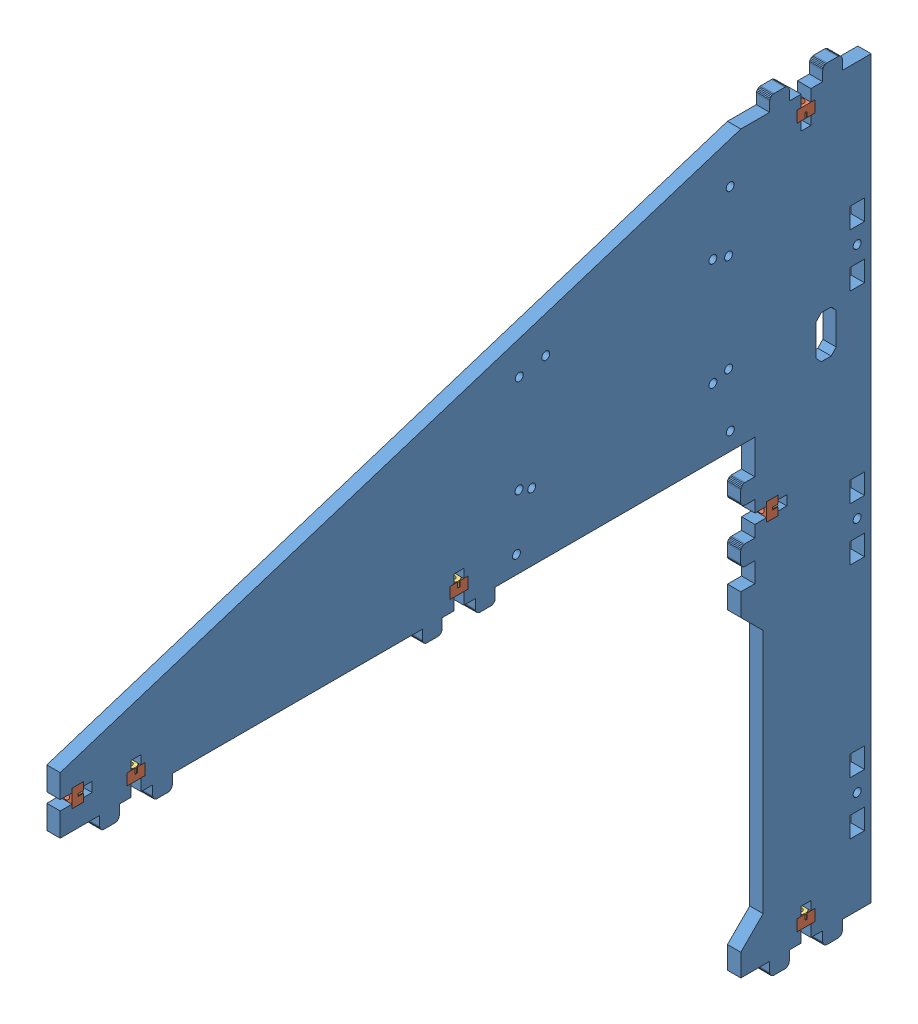
SolidWorks assembly Assembly Right Brace, configuration Valor predeterminado. Lengths in mm.
Overall size (7.94 342.6 363.9).
19 component instances, 3 part files, 21 mates.
Components (placement in the parent):
- Brace-1: Brace [Valor predeterminado] at (6 192.984 -281.4657) x (0 -1 0) z (-1 0 0) size (342.6 363.9 6)
- Assembly m3-nut-adapter + Nut DIN 934 - M3-1: Assembly m3-nut-adapter + Nut DIN 934 - M3 [Valor predeterminado] at (3 117.6 -228.1836) x (0 0 1) z (0 -1 0) size (8.25 7.94 5.1)
  - m3-nut-adapter-1: m3-nut-adapter [Valor predeterminado] at origin size (8 6 5.1)
  - Nut DIN 934 - M3-1: Nut DIN 934 - M3 [Valor predeterminado] at (0 0 3.9) x (0 0 1) z (-0.866025 -0.5 0) size (2.4 5.5 6.35)
- Assembly m3-nut-adapter + Nut DIN 934 - M3-2: Assembly m3-nut-adapter + Nut DIN 934 - M3 [Valor predeterminado] at (3 5.3 -72.4337) x (0 0 1) z (0 1 0) size (8.25 7.94 5.1)
  - m3-nut-adapter-1: m3-nut-adapter [Valor predeterminado] at origin size (8 6 5.1)
  - Nut DIN 934 - M3-1: Nut DIN 934 - M3 [Valor predeterminado] at (0 0 3.9) x (0 0 1) z (-0.866025 -0.5 0) size (2.4 5.5 6.35)
- Assembly m3-nut-adapter + Nut DIN 934 - M3-3: Assembly m3-nut-adapter + Nut DIN 934 - M3 [Valor predeterminado] at (3 5.3 72.4337) x (0 0 -1) z (0 1 0) size (8.25 7.94 5.1)
  - m3-nut-adapter-1: m3-nut-adapter [Valor predeterminado] at origin size (8 6 5.1)
  - Nut DIN 934 - M3-1: Nut DIN 934 - M3 [Valor predeterminado] at (0 0 3.9) x (0 0 1) z (-0.866025 -0.5 0) size (2.4 5.5 6.35)
- Assembly m3-nut-adapter + Nut DIN 934 - M3-4: Assembly m3-nut-adapter + Nut DIN 934 - M3 [Valor predeterminado] at (3 -31.7 -210.5336) x (0 -1 0) z (0 0 -1) size (8.25 7.94 5.1)
  - m3-nut-adapter-1: m3-nut-adapter [Valor predeterminado] at origin size (8 6 5.1)
  - Nut DIN 934 - M3-1: Nut DIN 934 - M3 [Valor predeterminado] at (0 0 3.9) x (0 0 1) z (-0.866025 -0.5 0) size (2.4 5.5 6.35)
- Assembly m3-nut-adapter + Nut DIN 934 - M3-5: Assembly m3-nut-adapter + Nut DIN 934 - M3 [Valor predeterminado] at (3 -201.6999 -228.1836) x (0 0 1) z (0 1 0) size (8.25 7.94 5.1)
  - m3-nut-adapter-1: m3-nut-adapter [Valor predeterminado] at origin size (8 6 5.1)
  - Nut DIN 934 - M3-1: Nut DIN 934 - M3 [Valor predeterminado] at (0 0 3.9) x (0 0 1) z (-0.866025 -0.5 0) size (2.4 5.5 6.35)
- Assembly m3-nut-adapter + Nut DIN 934 - M3-6: Assembly m3-nut-adapter + Nut DIN 934 - M3 [Valor predeterminado] at (3 12.8 101.1663) x (0 1 0) z (0 0 -1) size (8.25 7.94 5.1)
  - m3-nut-adapter-1: m3-nut-adapter [Valor predeterminado] at origin size (8 6 5.1)
  - Nut DIN 934 - M3-1: Nut DIN 934 - M3 [Valor predeterminado] at (0 0 3.9) x (0 0 1) z (-0.866025 -0.5 0) size (2.4 5.5 6.35)
Mates (geometry in assembly coordinates):
- Coincidente1: coincident: plane of ? through (0 192.984 -24.0321) normal (-1 0 0); plane of ? through (0 112.5 25.25) normal (-1 0 0)
- Coincidente2: coincident: plane of ? through (0 117.6 25.25) normal (0 0 1); plane of ? through (0 112.5 25.25) normal (0 0 -1)
- Coincidente3: coincident: plane of ? through (0 117.6 27.05) normal (0 -1 0); plane of ? through (3 117.6 29.25) normal (0 1 0)
- Coincidente4: coincident: plane of ? through (0 192.984 -24.0321) normal (-1 0 0); plane of ? through (0 10.4 333.8673) normal (-1 0 0)
- Coincidente5: coincident: plane of ? through (0 10.4 325.8673) normal (0 0 1); plane of ? through (0 10.4 325.8673) normal (0 0 -1)
- Coincidente6: coincident: plane of ? through (0 5.3 325.8673) normal (0 1 0); plane of ? through (3 5.3 329.8673) normal (0 -1 0)
- Coincidente7: coincident: plane of ? through (0 192.984 -24.0321) normal (-1 0 0); plane of ? through (0 10.4 180.9999) normal (-1 0 0)
- Coincidente8: coincident: plane of ? through (0 10.4 180.9999) normal (0 0 1); plane of ? through (6 10.4 180.9999) normal (0 0 -1)
- Coincidente9: coincident: plane of ? through (0 5.3 180.9999) normal (0 1 0); plane of ? through (3 5.3 184.9999) normal (0 -1 0)
- Coincidente10: coincident: plane of ? through (0 192.984 -24.0321) normal (-1 0 0); plane of ? through (0 -27.7 41.8) normal (-1 0 0)
- Coincidente11: coincident: plane of ? through (0 -35.7 46.9) normal (0 1 0); plane of ? through (0 -35.7 41.8) normal (0 -1 0)
- Coincidente12: coincident: plane of ? through (0 -33.9 46.9) normal (0 0 -1); plane of ? through (3 -31.7 46.9) normal (0 0 1)
- Coincidente13: coincident: plane of ? through (0 192.984 -24.0321) normal (-1 0 0); plane of ? through (0 -196.5999 25.25) normal (-1 0 0)
- Coincidente14: coincident: plane of ? through (0 -196.5999 25.25) normal (0 0 1); plane of ? through (6 -196.5999 25.25) normal (0 0 -1)
- Coincidente15: coincident: plane of ? through (0 -201.6999 25.25) normal (0 1 0); plane of ? through (3 -201.6999 29.25) normal (0 -1 0)
- Coincidente16: coincident: plane of ? through (0 192.984 -24.0321) normal (-1 0 0); plane of ? through (0 8.8 353.4999) normal (-1 0 0)
- Coincidente17: coincident: plane of ? through (0 8.8 358.5999) normal (0 1 0); plane of ? through (6 8.8 353.4999) normal (0 -1 0)
- Coincidente18: coincident: plane of ? through (0 10.6 358.5999) normal (0 0 -1); plane of ? through (3 12.8 358.5999) normal (0 0 1)
- Coincidente19: coincident: plane of ? through (0 0 52.2) normal (0 -1 0)
- Coincidente22: coincident: plane of ? through (0 192.984 -24.0321) normal (-1 0 0)
- Simétrico1: symmetric: plane of assembly; plane of assembly; plane of Brace-1 through (0 0 88.7336) normal (0 0 1); plane of Brace-1 through (0 -4.35 -88.7336) normal (0 0 -1); plane of assembly
